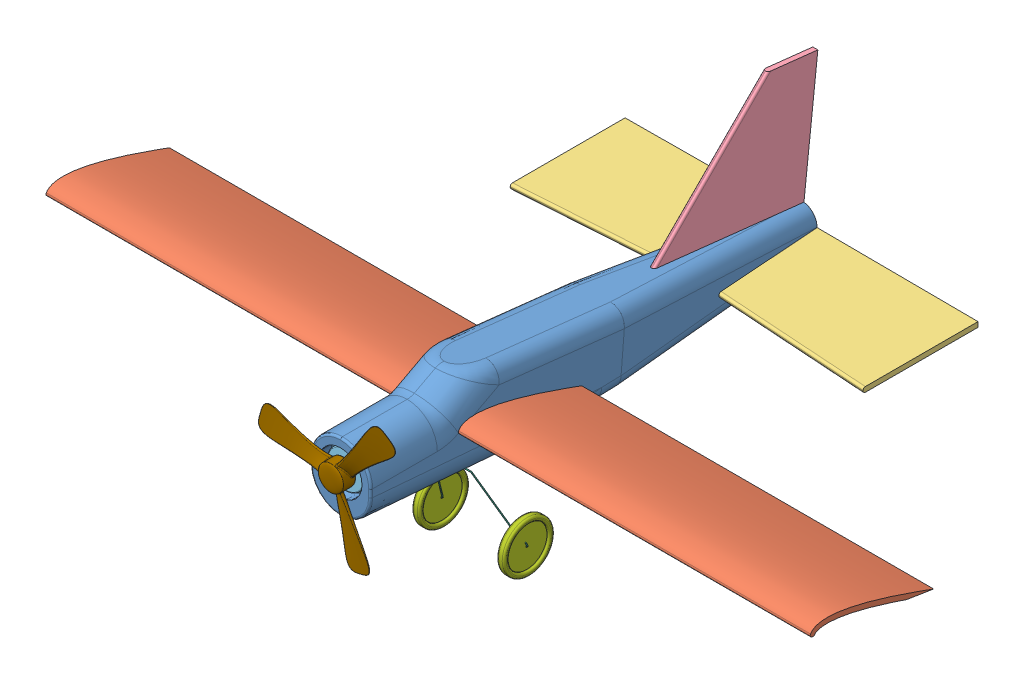
SolidWorks assembly final airplane, configuration Default. Lengths in mm.
Overall size (386.08 148.06 245.71).
13 component instances, 9 part files, 18 mates.
Components (placement in the parent):
- fuselage-1: fuselage [Default] at origin size (30.48 45.94 232.86)
- wing-2: wing [Default] at (15.24 21.2769 -43.881) x (1 0 0) z (0 0.156434 0.987688) size (177.8 6.71 63.3)
- h stab-3: h stab [Default] at (7.8614 12.4356 -232.9155) x (0.999983 -0.005779 0.000242) z (-0.000239 0.000405 1) size (81.28 2.54 58.05)
- h stab-4: h stab [Default] at (-7.8614 12.4356 -232.9155) x (-0.999983 -0.005779 0.000242) z (0.000239 0.000405 1) size (81.28 2.54 58.05)
- wing-3: wing [Default] at (-193.04 21.2769 -43.881) x (1 0 0) z (0 0.156434 0.987688) size (177.8 6.71 63.3)
- v stab-4: v stab [Default] at (0 30.0049 -157.1223) x (1 0 0) z (0 0.110432 0.993884) size (2.54 63.5 76.2)
- motor-1: motor [Default] at (0 19.05 -27.94) x (0 0 1) z (-1 0 0) size (38.35 23.62 23.62)
- wheel wire-1: wheel wire [Default] at (0 -3.5324 -55.88) x (1 0 0) z (0 -0.422618 0.906308) size (46.72 51.05 25.4)
  - wheel wire-1: wheel wire [Default] at origin size (45.82 38.61 0.51)
  - wheel-3: wheel [Default] at (-21.3937 -38.1 0) size (3.81 25.4 25.4)
  - wheel-4: wheel [Default] at (21.5119 -38.1 0) size (3.81 25.4 25.4)
- tail hook-1: tail hook [Default] at (0 0.0473 -181.1678) x (1 0 0) z (0 -0.02856 0.999592) size (0.51 19.28 43.06)
- propeller-2: propeller [Default] at (0 19.05 4.826) size (68.55 70.41 7.37)
Mates (geometry in assembly coordinates):
- Coincident1: coincident anti-aligned: plane of fuselage-1 through (15.24 41.91 -33.67) normal (1 0 0); plane of wing-2 through (15.24 21.2769 -43.881) normal (-1 0 0)
- Coincident2: coincident: point of fuselage-1; moEndPointRef_w of wing-2
- Angle1: planar angle = 0.15708 rad: plane of assembly through (0 0 0) normal (0 1 0); plane of assembly; plane of wing-2 through (15.24 21.2769 -43.881) normal (0 0.987688 -0.156434)
- Coincident22: coincident anti-aligned: plane of fuselage-1 through (7.62 -317.5082 -208.8841) normal (0.997564 -0.005793 -0.069516); plane of h stab-3 through (11.5858 13.7056 -179.5751) normal (-0.997564 0.005793 0.069516)
- Coincident26: coincident anti-aligned: plane of fuselage-1 through (15.24 41.91 -49.9762) normal (0 0.993884 -0.110432); plane of v stab-4 through (1.27 30.0049 -157.1223) normal (0 -0.993884 0.110432)
- Coincident27: coincident aligned: plane of v stab-4 through (0 30.0049 -157.1223) normal (1 0 0)
- Coincident28: coincident: plane of fuselage-1 through (15.24 21.59 -232.8562) normal (0 0 -1); line of v stab-4 through (1.27 21.59 -232.8562) axis (-1 0 0)
- Concentric3: concentric anti-aligned: cylinder of fuselage-1 through (0 19.05 -30.48) axis (0 0 1) radius 10.8572; circle of motor-1
- Distance7: distance = 2.54 mm aligned: plane of fuselage-1 through (15.24 0 0) normal (0 0 1); plane of motor-1 through (0 19.05 -2.54) normal (0 0 1)
- Tangent2: tangent aligned: plane of fuselage-1 through (15.24 1.27 -232.8562) normal (0 -0.999592 -0.02856); cylinder of wheel wire-1/wheel wire-1 through (-9.7702 -3.5324 -55.88) axis (1 0 0) radius 0.254
- Coincident30: coincident aligned: plane of wheel wire-1 through (0 -3.5324 -55.88) normal (1 0 0)
- Angle2: planar angle = 0.436332 rad: plane of assembly through (0 0 0) normal (0 0 1); plane of assembly; plane of wheel wire-1 through (0 -3.5324 -55.88) normal (0 -0.422618 0.906308)
- Distance8: distance = 55.88 mm: plane of fuselage-1 through (15.24 0 0) normal (0 0 1); cylinder of wheel wire-1/wheel wire-1 through (-9.7702 -3.5324 -55.88) axis (1 0 0) radius 0.254
- Coincident32: coincident aligned: plane of tail hook-1 through (0 0.0473 -181.1678) normal (1 0 0)
- Tangent6: tangent aligned: plane of fuselage-1 through (15.24 1.27 -232.8562) normal (0 -0.999592 -0.02856); cylinder of tail hook-1 through (0 0.0473 -181.1678) axis (0 0.02856 -0.999592) radius 0.254
- Coincident33: coincident: point of fuselage-1; cylinder of tail hook-1 through (0 -17.2857 -222.9798) axis (0 0.879952 -0.475063) radius 0.254
- Coincident35: coincident anti-aligned: plane of motor-1 through (0 19.05 10.414) normal (0 0 1); plane of propeller-2 through (0 19.05 10.414) normal (0 0 -1)
- Concentric4: concentric anti-aligned: cylinder of motor-1 through (0 19.05 10.414) axis (0 0 -1) radius 0.889; cylinder of propeller-2 through (0 19.05 3.556) axis (0 0 1) radius 6.35
